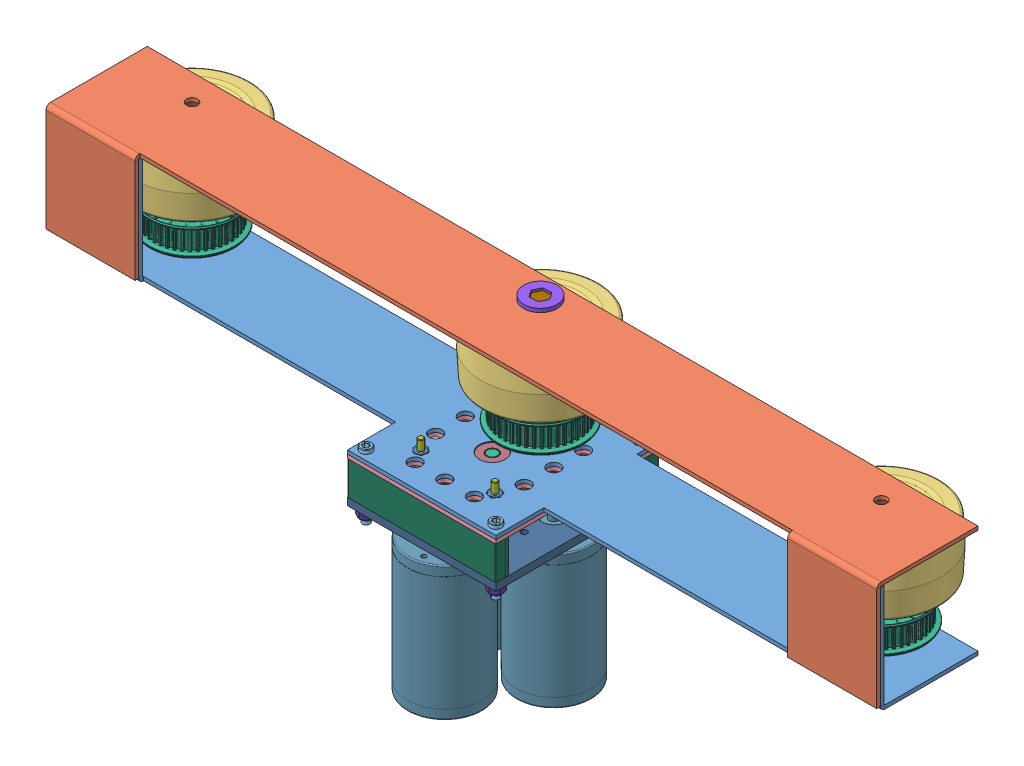
SolidWorks assembly wheel well assembly, configuration Default. Lengths in mm.
Overall size (722.23 256.81 237.72).
56 component instances, 28 part files, 11 mates.
Components (placement in the parent):
- interior wheel well-1: interior wheel well [Default] at (64.0134 461.709 590.6846) size (711.2 92.08 139.7)
- exterior wheel well-1: exterior wheel well [Default] at (562.6642 549.3506 593.8596) x (-1 0 0) z (0 0 1) size (711.2 92.07 86.72)
- wheel live axis-1: wheel live axis [Default] at (260.8798 526.3795 516.7847) x (0 -1 0) z (0.083749 0 0.996487) size (93.59 101.6 101.6)
  - colson wheel-1: colson wheel [Default] at (7.8533 43.785 105.4789) size (47.77 101.6 101.6)
  - hub live axis-1: hub live axis [Default] at (-17.6186 43.785 105.4789) x (0 -0.5 -0.866025) z (1 0 0) size (34.92 34.92 48.22)
  - versahub .5 in hex-2: versahub .5 in hex [Default] at (44.4376 43.785 105.4789) x (-1 0 0) z (0 0 -1) size (12.7 55.88 55.88)
  - pulley-1: pulley [Default] at (42.8501 43.785 105.4789) x (0 0.128986 0.991646) z (-1 0 0) size (73 73 23.01)
  - versahub 1.125 in bearing pilot-1: versahub 1.125 in bearing pilot [Default] at (38.0876 43.785 105.4789) x (0 -0.011158 0.999938) z (0 0.999938 0.011158) size (55.88 12.7 55.88)
  - hex bearing for live axis-1: hex bearing for live axis [Default] at (-30.3186 43.785 105.4789) x (0 -0.5 0.866025) z (0 0.866025 0.5) size (31.12 7.94 31.12)
- wheel dead axis-1: wheel dead axis [Default] at (704.3486 556.3797 624.3714) x (0 -1 0) z (-0.767501 0 -0.641048) size (87.16 101.6 101.6)
  - colson wheel-1: colson wheel [Default] at (34.5983 59.2472 75.5116) size (47.77 101.6 101.6)
  - hub dead axis-1: hub dead axis [Default] at (61.6576 59.2472 75.5116) x (0 0.55376 0.832676) z (-1 0 0) size (57.15 57.15 47.62)
  - bearing-1: bearing [Default] at (57.6889 59.2472 75.5116) size (7.14 22.23 22.23)
  - bearing-2: bearing [Default] at (17.2074 59.2472 75.5116) size (7.14 22.23 22.23)
  - versahub 1.125 in bearing pilot-1: versahub 1.125 in bearing pilot [Default] at (68.0076 59.2472 75.5116) x (0 1 0) z (0 0 1) size (55.88 12.7 55.88)
  - pulley-1: pulley [Default] at (90.5951 59.2472 75.5116) x (0 0 -1) z (1 0 0) size (73 73 23.01)
  - spacer for dead axis-2: spacer for dead axis [Default] at (6.0316 59.2472 75.5116) x (0 0.370269 -0.928924) z (1 0 0) size (30.04 30.04 11.18)
- wheel dead axis-2: wheel dead axis [Default] at (-40.9827 556.3797 545.9255) x (0 -1 0) z (0 0 1) size (87.16 101.6 101.6)
  - colson wheel-1: colson wheel [Default] at (34.5983 59.2472 75.5116) size (47.77 101.6 101.6)
  - hub dead axis-1: hub dead axis [Default] at (61.6576 59.2472 75.5116) x (0 0.55376 0.832676) z (-1 0 0) size (57.15 57.15 47.62)
  - bearing-1: bearing [Default] at (57.6889 59.2472 75.5116) size (7.14 22.23 22.23)
  - bearing-2: bearing [Default] at (17.2074 59.2472 75.5116) size (7.14 22.23 22.23)
  - versahub 1.125 in bearing pilot-1: versahub 1.125 in bearing pilot [Default] at (68.0076 59.2472 75.5116) x (0 1 0) z (0 0 1) size (55.88 12.7 55.88)
  - pulley-1: pulley [Default] at (90.5951 59.2472 75.5116) x (0 0 -1) z (1 0 0) size (73 73 23.01)
  - spacer for dead axis-2: spacer for dead axis [Default] at (6.0316 59.2472 75.5116) x (0 0.370269 -0.928924) z (1 0 0) size (30.04 30.04 11.18)
- 3CIM Gearbox with plate - AM14U-1: 3CIM Gearbox with plate - AM14U [Default] at (236.214 396.9903 599.8023) x (0.425715 0 -0.904857) z (0 -1 0) size (180.67 174.39 255.11)
  - 500 E-klip-1: 500 E-klip [Default] at (16.1298 77.6456 -43.9601) x (-0.987566 -0.157207 0) z (0 0 1) size (19.07 20.96 1.27)
  - FR6ZZ Bearing-1: FR6ZZ Bearing [Default] at (-13.0875 102.2889 -55.8473) x (0.991783 0.127931 0) z (0 0 -1) size (24.69 24.69 7.16)
  - CIM Motor SW-1: CIM Motor SW [Default] at (-100.8929 87.6226 -3.2185) x (0 1 0) z (0 0 -1) size (64.01 64.01 154.94)
  - ex-2508 Spacer-1: ex-2508 Spacer [Default] at (-92.2921 67.2369 -57.3713) x (0.425715 0.904857 0) z (0 0 1) size (127 14.35 28.75)
  - CIM Motor SW-2: CIM Motor SW [Default] at (-101.4872 6.1263 -3.2185) x (-0.762709 0.646742 0) z (0 0 -1) size (64.01 64.01 154.94)
  - Toughbox 14T Small Cluster-1: Toughbox 14T Small Cluster [Default] at (-21.1033 95.1629 -40.7851) x (-0.837052 0.547123 0) z (0 0 -1) size (20.03 20.32 15.25)
  - 14-20 Nylock Nut_97135A210-1: 14-20 Nylock Nut_97135A210 [Default] at (19.7748 14.5119 -22.2685) x (1 0 0) z (0 -1 0) size (11.11 8.13 12.83)
  - Toughbox 50T Large Cluster-1: Toughbox 50T Large Cluster [Default] at (-21.1033 95.1629 -40.7851) x (-0.055297 -0.99847 0) z (0 0 1) size (65.97 66.04 10.34)
  - 10-32 Nylock Jam Nut_90633A411-1: 10-32 Nylock Jam Nut_90633A411 [Default] at (-34.2188 136.4219 -60.5463) x (0.976554 -0.215274 0) z (0.215274 0.976554 0) size (9.53 4.55 11)
  - 14-20 Nylock Nut_97135A210-2: 14-20 Nylock Nut_97135A210 [Default] at (67.0932 115.0872 -22.2685) x (1 0 0) z (0 -1 0) size (11.11 8.13 12.83)
  - 14-20 Nylock Nut_97135A210-3: 14-20 Nylock Nut_97135A210 [Default] at (-92.2921 67.2369 -22.2685) x (1 0 0) z (0 -1 0) size (11.11 8.13 12.83)
  - ex-2508 Spacer-2: ex-2508 Spacer [Default] at (67.0932 115.0872 -57.3713) x (-0.425715 -0.904857 0) z (0 0 1) size (127 14.35 28.75)
  - Toughbox 50T Output-1: Toughbox 50T Output [Default] at (16.1298 77.6456 -45.1793) x (1 0 0) z (0 0 -1) size (65.97 66.04 10.62)
  - FR6ZZ Bearing-2: FR6ZZ Bearing [Default] at (-30.482 100.3659 -30.1425) x (-0.995778 -0.091798 0) z (0 0 1) size (24.69 24.69 7.16)
  - FR8ZZ Hex Bearing-1: FR8ZZ Hex Bearing [Default] at (16.1298 77.6456 -63.2666) size (31.12 31.12 7.93)
  - FR6ZZ Bearing-3: FR6ZZ Bearing [Default] at (7.2113 83.6032 -29.1773) x (-0.999955 -0.009486 0) z (0 0 1) size (24.69 24.69 7.16)
  - 3CIM TB Special Shaft Plate-1: 3CIM TB Special Shaft Plate [Default] at (16.1298 77.6456 -57.3713) x (0.425715 0.904857 0) z (0 0 1) size (127 139.7 3.17)
  - 10-32 Nylock Jam Nut_90633A411-2: 10-32 Nylock Jam Nut_90633A411 [Default] at (-61.2517 78.9634 -60.5463) x (0.733502 -0.679687 0) z (0.679687 0.733502 0) size (9.53 4.55 11)
  - SHCS 14-20 x 2-1: SHCS 14-20 x 2 [Default] at (-44.9737 167.8122 -67.0995) x (0.867127 -0.498087 0) z (0.498087 0.867127 0) size (9.53 57.35 9.53)
  - CIM Motor SW-3: CIM Motor SW [Default] at (-138.5887 47.3684 -3.2185) x (0.249226 0.968445 0) z (0 0 -1) size (64.01 64.01 154.94)
  - SHCS 14-20 x 2-2: SHCS 14-20 x 2 [Default] at (67.0932 115.0872 -67.0995) x (1 0 0) z (0 1 0) size (9.53 57.35 9.53)
  - TB Hex Shaft-1: TB Hex Shaft [Default] at (-63.6271 92.3312 -31.1331) x (-0.892349 -0.451347 0) z (-0.451347 0.892349 0) size (11 38.23 9.52)
  - 10-32x0625_shcs_HX-SHCS 0.19-32x1.375x1-C-1: 10-32x0625_shcs_HX-SHCS 0.19-32x1.375x1-C [Default] at (-34.2188 136.4219 -52.5453) x (0 0 -1) z (0.658531 0.752554 0) size (20.7 7.94 7.94)
  - Toughbox d29a-1: Toughbox d29a [Default] at (16.1298 77.6456 -22.2685) x (-0.904857 0.425715 0) z (0.425715 0.904857 0) size (19.05 6.1 50.8)
  - SHCS 14-20 x 2-3: SHCS 14-20 x 2 [Default] at (19.7748 14.5119 -67.0995) x (1 0 0) z (0 1 0) size (9.53 57.35 9.53)
  - 14-20 Nylock Nut_97135A210-4: 14-20 Nylock Nut_97135A210 [Default] at (-44.9737 167.8122 -22.2685) x (1 0 0) z (0 -1 0) size (11.11 8.13 12.83)
  - TB Output Shaft Hex L-Base 2-1: TB Output Shaft Hex L-Base 2 [Default] at (20.8476 119.155 -54.5773) x (0.5 0.866025 0) z (-0.866025 0.5 0) size (14.66 148.64 12.7)
  - 3CIM TB Special Motor Plate-1: 3CIM TB Special Motor Plate [Default] at (16.1298 77.6456 -57.1935) x (0.425715 0.904857 0) z (0 0 1) size (127 139.7 6.35)
  - 10-32x0625_shcs_HX-SHCS 0.19-32x1.375x1-C-2: 10-32x0625_shcs_HX-SHCS 0.19-32x1.375x1-C [Default] at (-61.2517 78.9634 -52.5453) x (0 0 -1) z (1 0 0) size (20.7 7.94 7.94)
  - SHCS 14-20 x 2-4: SHCS 14-20 x 2 [Default] at (-92.2921 67.2369 -67.0995) x (1 0 0) z (0 1 0) size (9.53 57.35 9.53)
Mates (geometry in assembly coordinates):
- Coincident1: coincident anti-aligned: plane of interior wheel well-1 through (-42.2612 378.1615 682.7596) normal (0 0 1); plane of exterior wheel well-1 through (668.9388 636.0731 682.7596) normal (0 0 -1)
- Coincident2: coincident anti-aligned: line of interior wheel well-1 through (592.7388 461.4481 682.7596) axis (1 0 0); line of exterior wheel well-1 through (668.9388 461.4481 682.7596) axis (-1 0 0)
- Coincident3: coincident anti-aligned: line of interior wheel well-1 through (668.9388 461.4481 682.7596) axis (0 1 0); line of exterior wheel well-1 through (668.9388 549.6115 682.7596) axis (0 -1 0)
- Coincident5: coincident anti-aligned: plane of exterior wheel well-1 through (668.9388 550.3481 599.212) normal (0 -1 0); plane of wheel live axis-1/hex bearing for live axis-1 through (306.7217 550.3481 632.3033) normal (0 1 0)
- Coincident7: coincident anti-aligned: plane of exterior wheel well-1 through (668.9388 550.3481 599.212) normal (0 -1 0); plane of wheel dead axis-2/spacer for dead axis-2 through (18.2645 550.3481 621.437) normal (0 1 0)
- Concentric2: concentric anti-aligned: circle of exterior wheel well-1; circle of wheel dead axis-2/spacer for dead axis-2
- Coincident13: coincident anti-aligned: plane of exterior wheel well-1 through (668.9388 550.3481 599.212) normal (0 -1 0); plane of wheel dead axis-1/spacer for dead axis-2 through (608.4132 550.3481 621.437) normal (0 1 0)
- Concentric3: concentric anti-aligned: circle of exterior wheel well-1; circle of wheel dead axis-1/spacer for dead axis-2
- Coincident14: coincident anti-aligned: plane of interior wheel well-1 through (-42.2612 457.5365 599.212) normal (0 -1 0); plane of 3CIM Gearbox with plate - AM14U-1/3CIM TB Special Shaft Plate-1 through (376.8388 457.5365 719.862) normal (0 1 0)
- Coincident15: coincident aligned: line of interior wheel well-1 through (249.8388 457.5365 719.862) axis (1 0 0); line of 3CIM Gearbox with plate - AM14U-1/3CIM TB Special Shaft Plate-1 through (249.8388 457.5365 719.862) axis (1 0 0)
- Coincident16: coincident aligned: line of interior wheel well-1 through (249.8388 457.5365 678.587) axis (0 0 1); line of 3CIM Gearbox with plate - AM14U-1/3CIM TB Special Shaft Plate-1 through (249.8388 457.5365 580.162) axis (0 0 1)
